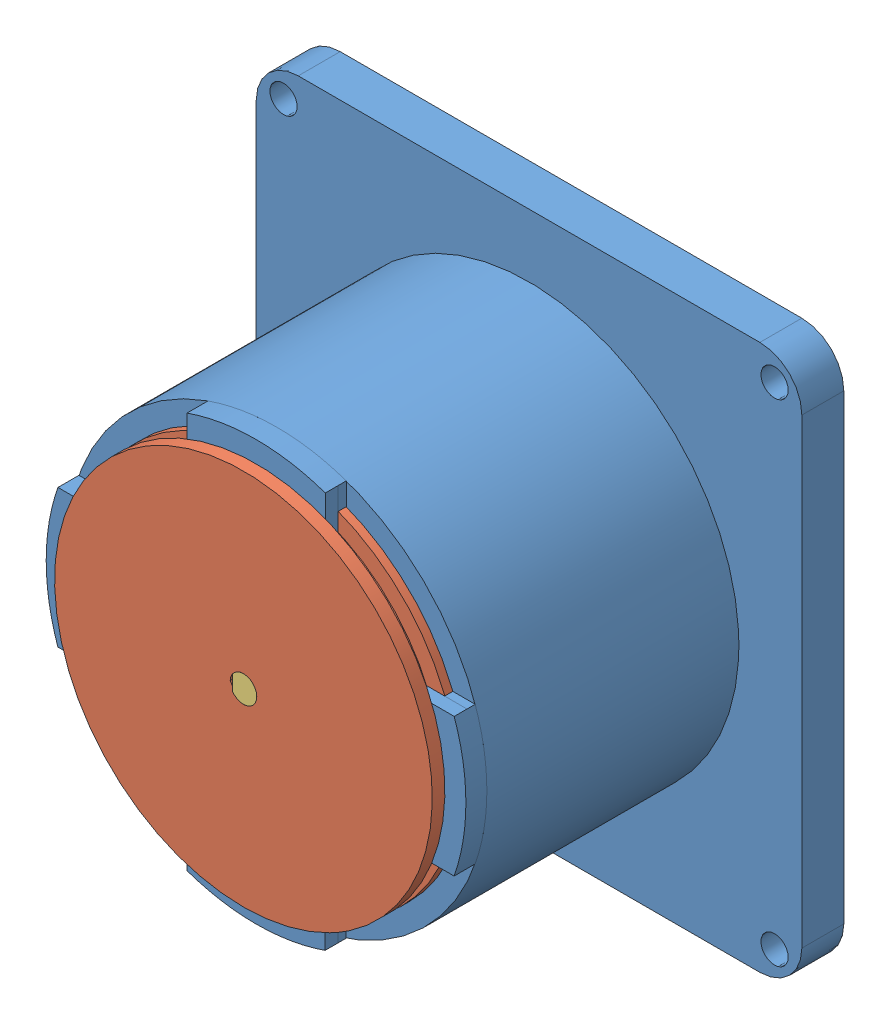
SolidWorks assembly 010, configuration Domyślna. Lengths in mm.
Overall size (130 130 78.05).
5 component instances, 4 part files, 5 mates.
Components (placement in the parent):
- 011-1: 011 [Domyślna] at (-12.9472 5.5241 130) size (130 130 75.05)
- 012-1: 012 [Domyślna] at (-12.9472 5.5241 208.05) x (0.509612 -0.860404 0) z (0 0 -1) size (90 90 8.6)
- 57cm12x-1: 57cm12x [Default] at (-12.9472 5.5241 185.05) x (0 1 0) z (0 0 1) size (57.15 58.15 68)
  - 57cm12x_01-1: 57cm12x_01 [Default] at origin size (6.35 6.35 11.4)
  - 57cm12x_02-1: 57cm12x_02 [Default] at origin size (57.15 58.15 56.6)
Mates (geometry in assembly coordinates):
- Wspólnie1: coincident anti-aligned: plane of 011-1 through (-12.9472 5.5241 195.05) normal (0 0 -1); plane of 57cm12x-1/57cm12x_02-1 through (-52.0242 15.8222 195.05) normal (0 0 1)
- Koncentryczne1: concentric aligned: circle of Podstawa-1; circle of 57cm12x-1/57cm12x_02-1
- Wspólnie3: coincident anti-aligned: plane of 011-1 through (-12.9472 5.5241 205.05) normal (0 0 1); plane of talerz do podstawy-1 through (-12.9472 5.5241 205.05) normal (0 0 -1)
- Koncentryczne2: concentric aligned: circle of 012-1; circle of 57cm12x-1/57cm12x_02-1
- Równolegle1: parallel aligned: plane of 011-1 through (52.0528 60.5241 140) normal (1 0 0); plane of 57cm12x-1/57cm12x_02-1 through (15.6278 -13.7259 140.05) normal (1 0 0)
